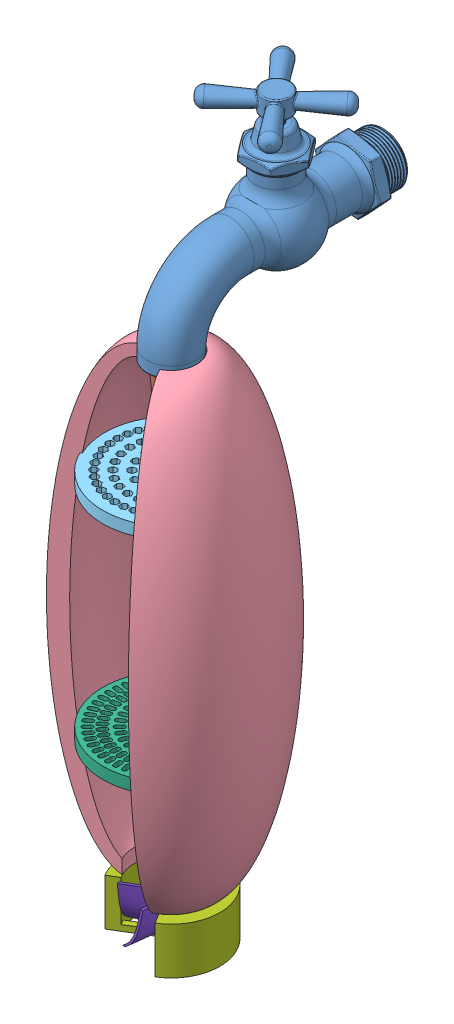
SolidWorks assembly assembly, configuration По умолчанию. Lengths in mm.
Overall size (107.15 292.95 145.15).
11 component instances, 11 part files, 10 mates.
Components (placement in the parent):
- faucet-1: faucet [По умолчанию] at origin size (40.75 78 102.07)
- water-1: water [По умолчанию] at (0 0.5 0) x (0.794594 0 0.607142) z (-0.607142 0 0.794594) size (17 161.5 17)
- water_back-1: water_back [По умолчанию] at (0 30 -90.75) x (0.743533 -0.6687 0) z (0 0 1) size (17 17 20)
- Part2-1: Part2 [Default] at (-9.679 -115.0527 4.7234) x (0.438572 0 0.898696) z (0 -1 0) size (80.13 80.13 198.53)
- Part1^assembly-1: Part1^assembly [Default] at origin (virtual)
- Part2^assembly-1: Part2^assembly [Default] at origin (virtual)
- Filtro 1-1: Filtro 1 [Default] at (0 -41.3168 0) x (0.991769 0 -0.128043) z (0 -1 0) size (58.68 58.68 5)
- Part3^assembly-1: Part3^assembly [Default] at origin (virtual)
- Filtro 2-1: Filtro 2 [Default] at (0 -136.3083 0) x (-0.987802 0 0.155713) z (0 -1 0) size (58.68 58.68 5)
- Diminución de intensidad-1: Diminución de intensidad [Default] at (0 -194.9461 0) x (0 -1 0) z (-0.51727 0 -0.855822) size (30 41.54 41.54)
- Aspas de disminución de intensidad-3: Aspas de disminución de intensidad [Default] at (0 -212.4461 0) x (0.837169 0 0.546944) z (0 -1 0) size (31.54 31.81 17.5)
Mates (geometry in assembly coordinates):
- Совпадение3: coincident anti-aligned: circle of faucet-1; circle of water_back-1
- Concentric1: concentric aligned: cylinder of faucet-1 through (0 0 0) axis (0 1 0) radius 10.5; circle of Part2-1
- Parallel2: parallel anti-aligned: plane of Filtro 2-1 through (0 -141.3083 0) normal (0 -1 0); plane of Part2-1 through (4.7234 -140.7188 9.679) normal (0 1 0)
- Concentric2: concentric aligned: cylinder of Filtro 2-1 through (0 -141.3083 0) axis (0 1 0) radius 29.34; cylinder of Part2-1 through (0 15.3592 0) axis (0 1 0) radius 24.3381
- Concentric3: concentric aligned: cylinder of Filtro 1-1 through (0 -46.3168 0) axis (0 1 0) radius 29.34; cylinder of Part2-1 through (0 15.3592 0) axis (0 1 0) radius 24.3381
- Parallel3: parallel anti-aligned: plane of Filtro 1-1 through (0 -46.3168 0) normal (0 -1 0); plane of Part2-1 through (4.7234 -45.7188 9.679) normal (0 1 0)
- Coincident2: coincident aligned: plane of Diminución de intensidad-1 through (10.7437 -194.2514 17.7754) normal (0 1 0); plane of Aspas de disminución de intensidad-3 through (0 -194.2514 0) normal (0 1 0)
- Concentric10: concentric aligned: cylinder of Part2-1 through (0 15.3592 0) axis (0 1 0) radius 15.77; cylinder of Diminución de intensidad-1 through (0 -156.9629 0) axis (0 1 0) radius 15.77
- Tangent1: tangent: circle of Part2-1; plane of Diminución de intensidad-1 through (10.7437 -194.2514 17.7754) normal (0 1 0)
- Concentric11: concentric anti-aligned: cylinder of Part2-1 through (0 15.3592 0) axis (0 1 0) radius 15.77; cylinder of Aspas de disminución de intensidad-3 through (0 -196.9814 0) axis (0 -1 0) radius 4.885
